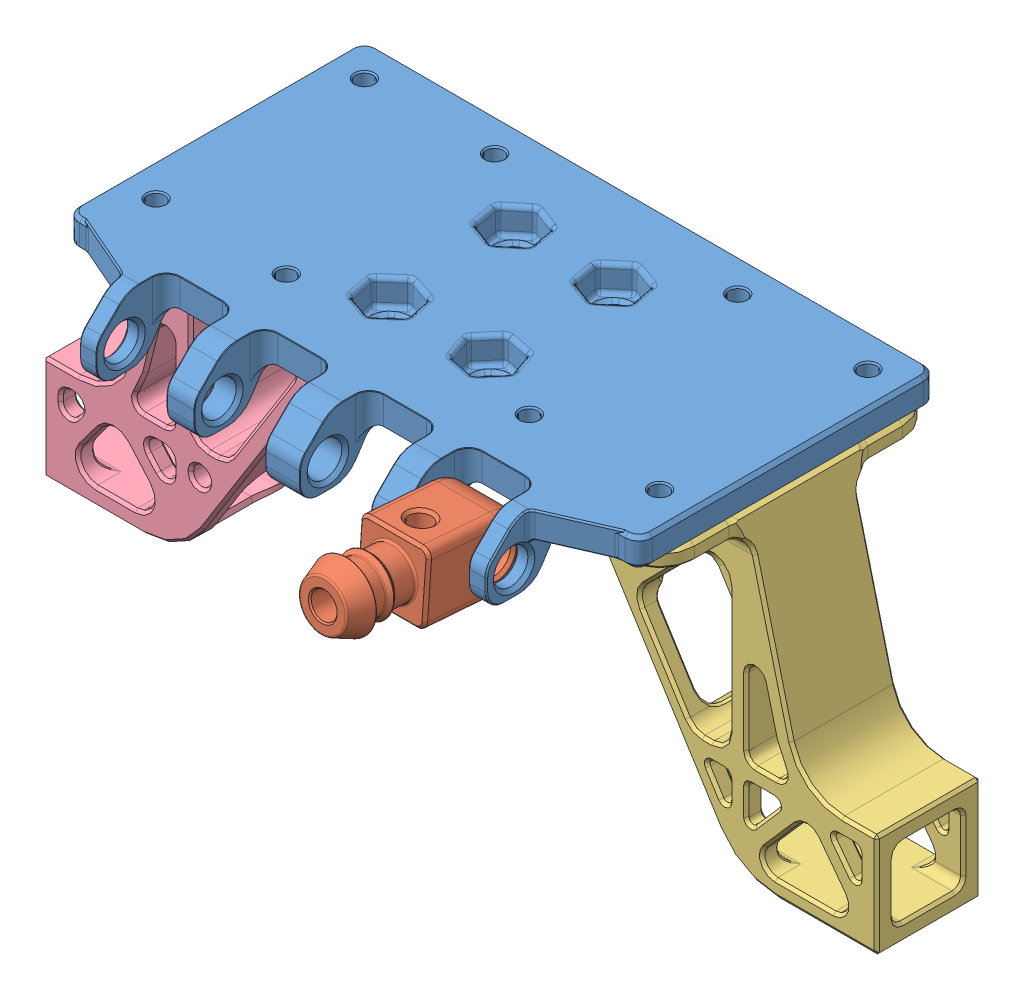
SolidWorks assembly Assem1, configuration Default. Lengths in mm.
Overall size (152.4 63.98 88.03).
4 component instances, 4 part files, 7 mates.
Components (placement in the parent):
- AARL_QR_FR_BO_012.3-1: AARL_QR_FR_BO_012.3 [Default] at (-48.7461 4.5595 17.9585) size (104.77 12.7 67.31)
- AARL_QR_PN_EP_001-1: AARL_QR_PN_EP_001 [Default] at (-21.1871 -0.965 52.8835) x (0 0.997217 -0.074552) z (-1 0 0) size (12.7 31.75 12.7)
- AARL_QR_FR_BO_017-1: AARL_QR_FR_BO_017 [Default] at (-32.8711 2.0195 16.0535) x (-1 0 0) z (0 0 1) size (60.32 58.74 50.8)
- AARL_QR_FR_BO_011-1: AARL_QR_FR_BO_011 [Default] at (-64.6211 2.0195 16.0535) x (1 0 0) z (0 0 -1) size (60.33 58.74 50.8)
Mates (geometry in assembly coordinates):
- Concentric1: concentric anti-aligned: cylinder of AARL_QR_FR_BO_012.3-1 through (3.6414 -0.965 52.8835) axis (-1 0 0) radius 3.175; cylinder of AARL_QR_PN_EP_001-1 through (-27.5371 -0.965 52.8835) axis (1 0 0) radius 3.175
- Coincident1: coincident anti-aligned: plane of AARL_QR_FR_BO_012.3-1 through (-27.5371 4.5595 57.9635) normal (1 0 0); plane of AARL_QR_PN_EP_001-1 through (-27.5371 -0.965 52.8835) normal (-1 0 0)
- Coincident3: coincident anti-aligned: plane of AARL_QR_FR_BO_012.3-1 through (-101.1336 2.0195 45.2635) normal (0 -1 0); plane of AARL_QR_FR_BO_017-1 through (-32.8711 2.0195 25.5785) normal (0 1 0)
- Concentric2: concentric anti-aligned: cylinder of AARL_QR_FR_BO_012.3-1 through (-2.7086 7.1005 -2.9965) axis (0 -1 0) radius 1.5875; cylinder of AARL_QR_FR_BO_017-1 through (-2.7086 -1.1555 -2.9965) axis (0 1 0) radius 1.5875
- Concentric3: concentric aligned: cylinder of AARL_QR_FR_BO_012.3-1 through (-2.7086 7.1005 35.1035) axis (0 -1 0) radius 1.5875; circle of AARL_QR_FR_BO_017-1
- Concentric7: concentric anti-aligned: cylinder of AARL_QR_FR_BO_012.3-1 through (-94.7836 7.1005 35.1035) axis (0 -1 0) radius 1.5875; cylinder of AARL_QR_FR_BO_011-1 through (-94.7836 -1.1555 35.1035) axis (0 1 0) radius 1.5875
- Coincident7: coincident aligned: plane of AARL_QR_FR_BO_012.3-1 through (-101.1336 7.0995 45.2635) normal (-1 0 0); plane of AARL_QR_FR_BO_011-1 through (-101.1336 -1.1555 25.5785) normal (-1 0 0)
